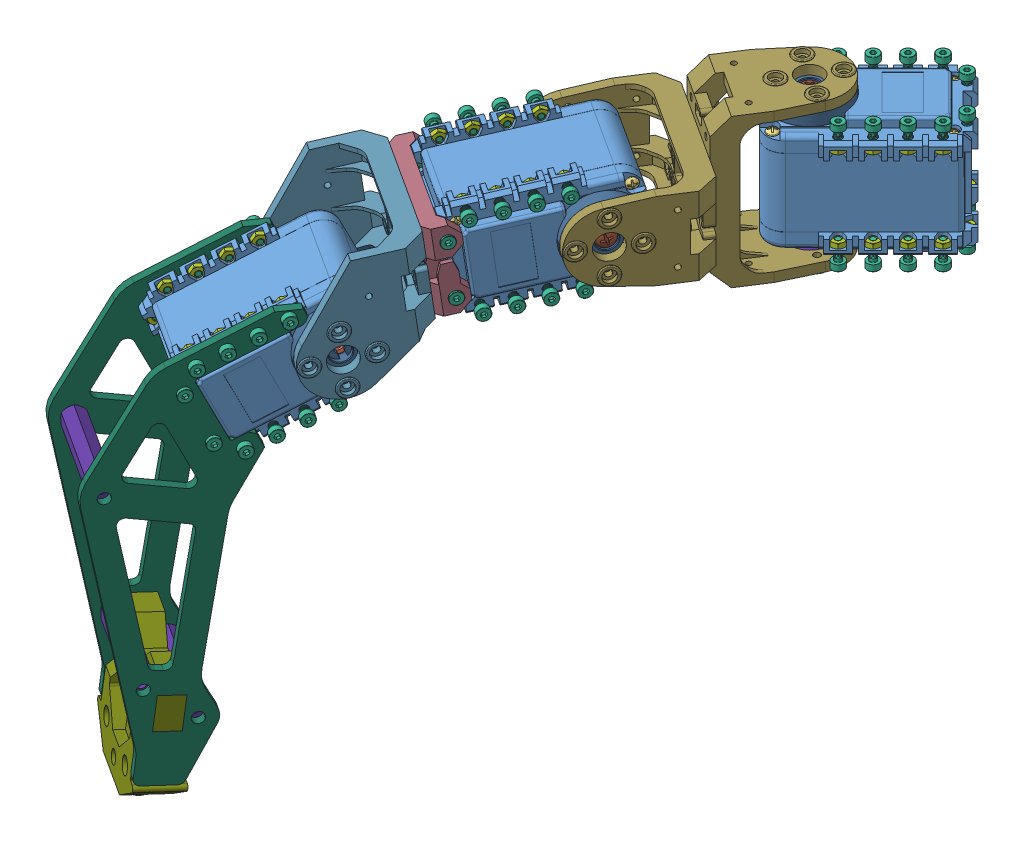
SolidWorks assembly Assambly Pedro Leg, configuration Predeterminado. Lengths in mm.
Overall size (165.19 178.65 220.71).
174 component instances, 18 part files, 61 mates.
Components (placement in the parent):
- AX-18F-1: AX-18F [Défaut] at (-83.9806 17.0398 384.115) x (-0.707107 0 -0.707107) z (0 1 0) size (32 50.04 41)
  - ASSY_DUMMY___-1: ASSY_DUMMY___ [Défaut] at origin size (32 50.04 38.37)
  - ASSY_GEAR-WHEEL___DUMMY-1: ASSY_GEAR-WHEEL___DUMMY [Défaut] at (0 0 -2) x (-1 0 0) z (0 0 1) size (6.5 6.5 5.51)
  - DX124_SCREW-COVER___-1: DX124_SCREW-COVER___ [Défaut] at (9.5 8.5 14.5) x (-1 0 0) z (0 1 0) size (3.5 30.7 3.5)
  - DX124_SCREW-COVER___-2: DX124_SCREW-COVER___ [Défaut] at (-9.5 8.5 14.5) x (-1 0 0) z (0 1 0) size (3.5 30.7 3.5)
  - DX124_SCREW-COVER___-3: DX124_SCREW-COVER___ [Défaut] at (10.5 -33 14.5) x (-1 0 0) z (0 1 0) size (3.5 30.7 3.5)
  - DX124_SCREW-COVER___-4: DX124_SCREW-COVER___ [Défaut] at (-10.5 -33 14.5) x (-1 0 0) z (0 1 0) size (3.5 30.7 3.5)
  - 099990987____-1: 099990987____ [Défaut] at (5.05 -15.19 -9.75) x (1 0 0) z (0 1 0) size (9.9 9.43 4.9)
  - 099990987____-2: 099990987____ [Défaut] at (-4.95 -15.19 -9.75) x (1 0 0) z (0 1 0) size (9.9 9.43 4.9)
  - DC04_B01_INSERT_M3-1: DC04_B01_INSERT_M3 [Défaut] at (0 0 -18.4) x (-1 0 0) z (0 1 0) size (4.98 7 4.98)
  - socket head cap screw_iso-1: socket head cap screw_iso [ISO 4762 M2 x 6 --- 6S] at (-13.5 -6.5 20.5) x (0 0 -1) z (1 0 0) size (8 3.8 3.8)
  - hex nut style 1 gradeab_iso-1: hex nut style 1 gradeab_iso [Hexagon Nut ISO - 4032 - M2 - D - S] at (-13.5 -6.5 14) x (0 1 0) z (0 0 1) size (4 4.62 1.6)
  - hex nut style 1 gradeab_iso-2: hex nut style 1 gradeab_iso [Hexagon Nut ISO - 4032 - M2 - D - S] at (-13.5 -14.5 14) x (0 1 0) z (0 0 1) size (4 4.62 1.6)
  - hex nut style 1 gradeab_iso-3: hex nut style 1 gradeab_iso [Hexagon Nut ISO - 4032 - M2 - D - S] at (-13.5 -22.5 14) x (0 1 0) z (0 0 1) size (4 4.62 1.6)
  - socket head cap screw_iso-2: socket head cap screw_iso [ISO 4762 M2 x 6 --- 6S] at (-13.5 -14.5 20.5) x (0 0 -1) z (1 0 0) size (8 3.8 3.8)
  - socket head cap screw_iso-3: socket head cap screw_iso [ISO 4762 M2 x 6 --- 6S] at (-13.5 -22.5 20.5) x (0 0 -1) z (1 0 0) size (8 3.8 3.8)
  - socket head cap screw_iso-4: socket head cap screw_iso [ISO 4762 M2 x 6 --- 6S] at (-13.5 -30.5 20.5) x (0 0 -1) z (1 0 0) size (8 3.8 3.8)
  - hex nut style 1 gradeab_iso-4: hex nut style 1 gradeab_iso [Hexagon Nut ISO - 4032 - M2 - D - S] at (-13.5 -30.5 14) x (0 1 0) z (0 0 1) size (4 4.62 1.6)
  - hex nut style 1 gradeab_iso-5: hex nut style 1 gradeab_iso [Hexagon Nut ISO - 4032 - M2 - D - S] at (13.5 -6.5 12.4001) x (0 1 0) z (0 0 -1) size (4 4.62 1.6)
  - socket head cap screw_iso-5: socket head cap screw_iso [ISO 4762 M2 x 6 --- 6S] at (13.5 -6.5 20.5) x (0 0 -1) z (1 0 0) size (8 3.8 3.8)
  - hex nut style 1 gradeab_iso-6: hex nut style 1 gradeab_iso [Hexagon Nut ISO - 4032 - M2 - D - S] at (13.5 -14.5 12.4001) x (0 1 0) z (0 0 -1) size (4 4.62 1.6)
  - hex nut style 1 gradeab_iso-7: hex nut style 1 gradeab_iso [Hexagon Nut ISO - 4032 - M2 - D - S] at (13.5 -22.5 12.4001) x (0 1 0) z (0 0 -1) size (4 4.62 1.6)
  - socket head cap screw_iso-6: socket head cap screw_iso [ISO 4762 M2 x 6 --- 6S] at (13.5 -14.5 20.5) x (0 0 -1) z (1 0 0) size (8 3.8 3.8)
  - socket head cap screw_iso-7: socket head cap screw_iso [ISO 4762 M2 x 6 --- 6S] at (13.5 -22.5 20.5) x (0 0 -1) z (1 0 0) size (8 3.8 3.8)
  - socket head cap screw_iso-8: socket head cap screw_iso [ISO 4762 M2 x 6 --- 6S] at (13.5 -30.5 20.5) x (0 0 -1) z (1 0 0) size (8 3.8 3.8)
  - hex nut style 1 gradeab_iso-8: hex nut style 1 gradeab_iso [Hexagon Nut ISO - 4032 - M2 - D - S] at (13.5 -30.5 12.4001) x (0 1 0) z (0 0 -1) size (4 4.62 1.6)
  - socket head cap screw_iso-9: socket head cap screw_iso [ISO 4762 M2 x 6 --- 6S] at (-13.5 -6.5 -20.5) x (0 0 1) z (-1 0 0) size (8 3.8 3.8)
  - hex nut style 1 gradeab_iso-9: hex nut style 1 gradeab_iso [Hexagon Nut ISO - 4032 - M2 - D - S] at (-13.5 -6.5 -12.4001) x (0 1 0) z (0 0 1) size (4 4.62 1.6)
  - hex nut style 1 gradeab_iso-10: hex nut style 1 gradeab_iso [Hexagon Nut ISO - 4032 - M2 - D - S] at (-13.5 -14.5 -12.4001) x (0 1 0) z (0 0 1) size (4 4.62 1.6)
  - hex nut style 1 gradeab_iso-11: hex nut style 1 gradeab_iso [Hexagon Nut ISO - 4032 - M2 - D - S] at (-13.5 -22.5 -12.4001) x (0 1 0) z (0 0 1) size (4 4.62 1.6)
  - socket head cap screw_iso-10: socket head cap screw_iso [ISO 4762 M2 x 6 --- 6S] at (-13.5 -14.5 -20.5) x (0 0 1) z (-1 0 0) size (8 3.8 3.8)
  - socket head cap screw_iso-11: socket head cap screw_iso [ISO 4762 M2 x 6 --- 6S] at (-13.5 -22.5 -20.5) x (0 0 1) z (-1 0 0) size (8 3.8 3.8)
  - socket head cap screw_iso-12: socket head cap screw_iso [ISO 4762 M2 x 6 --- 6S] at (-13.5 -30.5 -20.5) x (0 0 1) z (-1 0 0) size (8 3.8 3.8)
  - hex nut style 1 gradeab_iso-12: hex nut style 1 gradeab_iso [Hexagon Nut ISO - 4032 - M2 - D - S] at (-13.5 -30.5 -12.4001) x (0 1 0) z (0 0 1) size (4 4.62 1.6)
  - hex nut style 1 gradeab_iso-13: hex nut style 1 gradeab_iso [Hexagon Nut ISO - 4032 - M2 - D - S] at (13.5 -6.5 -14) x (0 1 0) z (0 0 -1) size (4 4.62 1.6)
  - socket head cap screw_iso-13: socket head cap screw_iso [ISO 4762 M2 x 6 --- 6S] at (13.5 -6.5 -20.5) x (0 0 1) z (-1 0 0) size (8 3.8 3.8)
  - hex nut style 1 gradeab_iso-14: hex nut style 1 gradeab_iso [Hexagon Nut ISO - 4032 - M2 - D - S] at (13.5 -14.5 -14) x (0 1 0) z (0 0 -1) size (4 4.62 1.6)
  - hex nut style 1 gradeab_iso-15: hex nut style 1 gradeab_iso [Hexagon Nut ISO - 4032 - M2 - D - S] at (13.5 -22.5 -14) x (0 1 0) z (0 0 -1) size (4 4.62 1.6)
  - socket head cap screw_iso-14: socket head cap screw_iso [ISO 4762 M2 x 6 --- 6S] at (13.5 -14.5 -20.5) x (0 0 1) z (-1 0 0) size (8 3.8 3.8)
  - socket head cap screw_iso-15: socket head cap screw_iso [ISO 4762 M2 x 6 --- 6S] at (13.5 -22.5 -20.5) x (0 0 1) z (-1 0 0) size (8 3.8 3.8)
  - socket head cap screw_iso-16: socket head cap screw_iso [ISO 4762 M2 x 6 --- 6S] at (13.5 -30.5 -20.5) x (0 0 1) z (-1 0 0) size (8 3.8 3.8)
  - hex nut style 1 gradeab_iso-16: hex nut style 1 gradeab_iso [Hexagon Nut ISO - 4032 - M2 - D - S] at (13.5 -30.5 -14) x (0 1 0) z (0 0 -1) size (4 4.62 1.6)
  - socket head cap screw_iso-17: socket head cap screw_iso [ISO 4762 M2 x 5 --- 5S] at (-8 -36 19.6) x (0 0 -1) z (1 0 0) size (7 3.8 3.8)
  - hex nut style 1 gradeab_iso-17: hex nut style 1 gradeab_iso [Hexagon Nut ISO - 4032 - M2 - D - S] at (-8 -36 14) x (-1 0 0) z (0 0 1) size (4 4.62 1.6)
  - hex nut style 1 gradeab_iso-18: hex nut style 1 gradeab_iso [Hexagon Nut ISO - 4032 - M2 - D - S] at (8 -36 14) x (-1 0 0) z (0 0 1) size (4 4.62 1.6)
  - socket head cap screw_iso-18: socket head cap screw_iso [ISO 4762 M2 x 5 --- 5S] at (8 -36 19.6) x (0 0 -1) z (1 0 0) size (7 3.8 3.8)
  - socket head cap screw_iso-19: socket head cap screw_iso [ISO 4762 M2 x 5 --- 5S] at (-8 -36 -19.6) x (0 0 1) z (-1 0 0) size (7 3.8 3.8)
  - hex nut style 1 gradeab_iso-19: hex nut style 1 gradeab_iso [Hexagon Nut ISO - 4032 - M2 - D - S] at (-8 -36 -12.4001) x (-1 0 0) z (0 0 1) size (4 4.62 1.6)
  - hex nut style 1 gradeab_iso-20: hex nut style 1 gradeab_iso [Hexagon Nut ISO - 4032 - M2 - D - S] at (8 -36 -12.4001) x (-1 0 0) z (0 0 1) size (4 4.62 1.6)
  - socket head cap screw_iso-20: socket head cap screw_iso [ISO 4762 M2 x 5 --- 5S] at (8 -36 -19.6) x (0 0 1) z (-1 0 0) size (7 3.8 3.8)
- PBPF-WA-1: PBPF-WA [Predeterminado] at (-83.9806 -3.0702 384.115) x (0.035761 0 0.99936) z (-0.99936 0 0.035761) size (12 1.9 12)
- PBPF-BU-1: PBPF-BU [Predeterminado] at (-83.9806 -1.4202 384.115) x (0.260833 0 0.965384) z (0.965384 0 -0.260833) size (10 7.1 10)
- DC04_B01_HORN2_DUMMY-1: DC04_B01_HORN2_DUMMY [Défaut] at (-83.9806 36.1398 384.115) x (-0.707107 0 0.707107) z (0 1 0) size (22 22 6.7)
- BHS_M2_6X8-1: BHS_M2_6X8 [Défaut] at (-83.9806 36.5898 384.115) size (5.5 9.6 5.5)
- PFP04-F2-2: PFP04-F2 [Défaut] at (-83.9806 16.9798 384.115) x (0 1 0) z (-0.542867 0 0.839819) size (48.81 25 37)
- BHS_M2_6X8-2: BHS_M2_6X8 [Défaut] at (-83.9806 -6.5202 384.115) x (-0.76654 0 0.642197) z (0.642197 0 0.76654) size (5.5 9.6 5.5)
- PFP04-F2-3: PFP04-F2 [Défaut] at (-112.2097 16.9798 427.7856) x (-0.839819 0 -0.542867) z (0.542867 0 -0.839819) size (48.81 25 37)
- AX-18F-14: AX-18F [Défaut] at (-112.1593 16.9798 427.8182) x (0.066454 -0.992479 -0.102804) z (0.839819 0 0.542867) size (32 50.04 41)
  - ASSY_DUMMY___-1: ASSY_DUMMY___ [Défaut] at origin size (32 50.04 38.37)
  - ASSY_GEAR-WHEEL___DUMMY-1: ASSY_GEAR-WHEEL___DUMMY [Défaut] at (0 0 -2) x (-1 0 0) z (0 0 1) size (6.5 6.5 5.51)
  - DX124_SCREW-COVER___-1: DX124_SCREW-COVER___ [Défaut] at (9.5 8.5 14.5) x (-1 0 0) z (0 1 0) size (3.5 30.7 3.5)
  - DX124_SCREW-COVER___-2: DX124_SCREW-COVER___ [Défaut] at (-9.5 8.5 14.5) x (-1 0 0) z (0 1 0) size (3.5 30.7 3.5)
  - DX124_SCREW-COVER___-3: DX124_SCREW-COVER___ [Défaut] at (10.5 -33 14.5) x (-1 0 0) z (0 1 0) size (3.5 30.7 3.5)
  - DX124_SCREW-COVER___-4: DX124_SCREW-COVER___ [Défaut] at (-10.5 -33 14.5) x (-1 0 0) z (0 1 0) size (3.5 30.7 3.5)
  - 099990987____-1: 099990987____ [Défaut] at (5.05 -15.19 -9.75) x (1 0 0) z (0 1 0) size (9.9 9.43 4.9)
  - 099990987____-2: 099990987____ [Défaut] at (-4.95 -15.19 -9.75) x (1 0 0) z (0 1 0) size (9.9 9.43 4.9)
  - DC04_B01_INSERT_M3-1: DC04_B01_INSERT_M3 [Défaut] at (0 0 -18.4) x (-1 0 0) z (0 1 0) size (4.98 7 4.98)
  - socket head cap screw_iso-1: socket head cap screw_iso [ISO 4762 M2 x 6 --- 6S] at (-13.5 -6.5 20.5) x (0 0 -1) z (1 0 0) size (8 3.8 3.8)
  - hex nut style 1 gradeab_iso-1: hex nut style 1 gradeab_iso [Hexagon Nut ISO - 4032 - M2 - D - S] at (-13.5 -6.5 14) x (0 1 0) z (0 0 1) size (4 4.62 1.6)
  - hex nut style 1 gradeab_iso-2: hex nut style 1 gradeab_iso [Hexagon Nut ISO - 4032 - M2 - D - S] at (-13.5 -14.5 14) x (0 1 0) z (0 0 1) size (4 4.62 1.6)
  - hex nut style 1 gradeab_iso-3: hex nut style 1 gradeab_iso [Hexagon Nut ISO - 4032 - M2 - D - S] at (-13.5 -22.5 14) x (0 1 0) z (0 0 1) size (4 4.62 1.6)
  - socket head cap screw_iso-2: socket head cap screw_iso [ISO 4762 M2 x 6 --- 6S] at (-13.5 -14.5 20.5) x (0 0 -1) z (1 0 0) size (8 3.8 3.8)
  - socket head cap screw_iso-3: socket head cap screw_iso [ISO 4762 M2 x 6 --- 6S] at (-13.5 -22.5 20.5) x (0 0 -1) z (1 0 0) size (8 3.8 3.8)
  - socket head cap screw_iso-4: socket head cap screw_iso [ISO 4762 M2 x 6 --- 6S] at (-13.5 -30.5 20.5) x (0 0 -1) z (1 0 0) size (8 3.8 3.8)
  - hex nut style 1 gradeab_iso-4: hex nut style 1 gradeab_iso [Hexagon Nut ISO - 4032 - M2 - D - S] at (-13.5 -30.5 14) x (0 1 0) z (0 0 1) size (4 4.62 1.6)
  - hex nut style 1 gradeab_iso-5: hex nut style 1 gradeab_iso [Hexagon Nut ISO - 4032 - M2 - D - S] at (13.5 -6.5 12.4001) x (0 1 0) z (0 0 -1) size (4 4.62 1.6)
  - socket head cap screw_iso-5: socket head cap screw_iso [ISO 4762 M2 x 6 --- 6S] at (13.5 -6.5 20.5) x (0 0 -1) z (1 0 0) size (8 3.8 3.8)
  - hex nut style 1 gradeab_iso-6: hex nut style 1 gradeab_iso [Hexagon Nut ISO - 4032 - M2 - D - S] at (13.5 -14.5 12.4001) x (0 1 0) z (0 0 -1) size (4 4.62 1.6)
  - hex nut style 1 gradeab_iso-7: hex nut style 1 gradeab_iso [Hexagon Nut ISO - 4032 - M2 - D - S] at (13.5 -22.5 12.4001) x (0 1 0) z (0 0 -1) size (4 4.62 1.6)
  - socket head cap screw_iso-6: socket head cap screw_iso [ISO 4762 M2 x 6 --- 6S] at (13.5 -14.5 20.5) x (0 0 -1) z (1 0 0) size (8 3.8 3.8)
  - socket head cap screw_iso-7: socket head cap screw_iso [ISO 4762 M2 x 6 --- 6S] at (13.5 -22.5 20.5) x (0 0 -1) z (1 0 0) size (8 3.8 3.8)
  - socket head cap screw_iso-8: socket head cap screw_iso [ISO 4762 M2 x 6 --- 6S] at (13.5 -30.5 20.5) x (0 0 -1) z (1 0 0) size (8 3.8 3.8)
  - hex nut style 1 gradeab_iso-8: hex nut style 1 gradeab_iso [Hexagon Nut ISO - 4032 - M2 - D - S] at (13.5 -30.5 12.4001) x (0 1 0) z (0 0 -1) size (4 4.62 1.6)
  - socket head cap screw_iso-9: socket head cap screw_iso [ISO 4762 M2 x 6 --- 6S] at (-13.5 -6.5 -20.5) x (0 0 1) z (-1 0 0) size (8 3.8 3.8)
  - hex nut style 1 gradeab_iso-9: hex nut style 1 gradeab_iso [Hexagon Nut ISO - 4032 - M2 - D - S] at (-13.5 -6.5 -12.4001) x (0 1 0) z (0 0 1) size (4 4.62 1.6)
  - hex nut style 1 gradeab_iso-10: hex nut style 1 gradeab_iso [Hexagon Nut ISO - 4032 - M2 - D - S] at (-13.5 -14.5 -12.4001) x (0 1 0) z (0 0 1) size (4 4.62 1.6)
  - hex nut style 1 gradeab_iso-11: hex nut style 1 gradeab_iso [Hexagon Nut ISO - 4032 - M2 - D - S] at (-13.5 -22.5 -12.4001) x (0 1 0) z (0 0 1) size (4 4.62 1.6)
  - socket head cap screw_iso-10: socket head cap screw_iso [ISO 4762 M2 x 6 --- 6S] at (-13.5 -14.5 -20.5) x (0 0 1) z (-1 0 0) size (8 3.8 3.8)
  - socket head cap screw_iso-11: socket head cap screw_iso [ISO 4762 M2 x 6 --- 6S] at (-13.5 -22.5 -20.5) x (0 0 1) z (-1 0 0) size (8 3.8 3.8)
  - socket head cap screw_iso-12: socket head cap screw_iso [ISO 4762 M2 x 6 --- 6S] at (-13.5 -30.5 -20.5) x (0 0 1) z (-1 0 0) size (8 3.8 3.8)
  - hex nut style 1 gradeab_iso-12: hex nut style 1 gradeab_iso [Hexagon Nut ISO - 4032 - M2 - D - S] at (-13.5 -30.5 -12.4001) x (0 1 0) z (0 0 1) size (4 4.62 1.6)
  - hex nut style 1 gradeab_iso-13: hex nut style 1 gradeab_iso [Hexagon Nut ISO - 4032 - M2 - D - S] at (13.5 -6.5 -14) x (0 1 0) z (0 0 -1) size (4 4.62 1.6)
  - socket head cap screw_iso-13: socket head cap screw_iso [ISO 4762 M2 x 6 --- 6S] at (13.5 -6.5 -20.5) x (0 0 1) z (-1 0 0) size (8 3.8 3.8)
  - hex nut style 1 gradeab_iso-14: hex nut style 1 gradeab_iso [Hexagon Nut ISO - 4032 - M2 - D - S] at (13.5 -14.5 -14) x (0 1 0) z (0 0 -1) size (4 4.62 1.6)
  - hex nut style 1 gradeab_iso-15: hex nut style 1 gradeab_iso [Hexagon Nut ISO - 4032 - M2 - D - S] at (13.5 -22.5 -14) x (0 1 0) z (0 0 -1) size (4 4.62 1.6)
  - socket head cap screw_iso-14: socket head cap screw_iso [ISO 4762 M2 x 6 --- 6S] at (13.5 -14.5 -20.5) x (0 0 1) z (-1 0 0) size (8 3.8 3.8)
  - socket head cap screw_iso-15: socket head cap screw_iso [ISO 4762 M2 x 6 --- 6S] at (13.5 -22.5 -20.5) x (0 0 1) z (-1 0 0) size (8 3.8 3.8)
  - socket head cap screw_iso-16: socket head cap screw_iso [ISO 4762 M2 x 6 --- 6S] at (13.5 -30.5 -20.5) x (0 0 1) z (-1 0 0) size (8 3.8 3.8)
  - hex nut style 1 gradeab_iso-16: hex nut style 1 gradeab_iso [Hexagon Nut ISO - 4032 - M2 - D - S] at (13.5 -30.5 -14) x (0 1 0) z (0 0 -1) size (4 4.62 1.6)
  - socket head cap screw_iso-17: socket head cap screw_iso [ISO 4762 M2 x 5 --- 5S] at (-8 -36 19.6) x (0 0 -1) z (1 0 0) size (7 3.8 3.8)
  - hex nut style 1 gradeab_iso-17: hex nut style 1 gradeab_iso [Hexagon Nut ISO - 4032 - M2 - D - S] at (-8 -36 14) x (-1 0 0) z (0 0 1) size (4 4.62 1.6)
  - hex nut style 1 gradeab_iso-18: hex nut style 1 gradeab_iso [Hexagon Nut ISO - 4032 - M2 - D - S] at (8 -36 14) x (-1 0 0) z (0 0 1) size (4 4.62 1.6)
  - socket head cap screw_iso-18: socket head cap screw_iso [ISO 4762 M2 x 5 --- 5S] at (8 -36 19.6) x (0 0 -1) z (1 0 0) size (7 3.8 3.8)
  - socket head cap screw_iso-19: socket head cap screw_iso [ISO 4762 M2 x 5 --- 5S] at (-8 -36 -19.6) x (0 0 1) z (-1 0 0) size (7 3.8 3.8)
  - hex nut style 1 gradeab_iso-19: hex nut style 1 gradeab_iso [Hexagon Nut ISO - 4032 - M2 - D - S] at (-8 -36 -12.4001) x (-1 0 0) z (0 0 1) size (4 4.62 1.6)
  - hex nut style 1 gradeab_iso-20: hex nut style 1 gradeab_iso [Hexagon Nut ISO - 4032 - M2 - D - S] at (8 -36 -12.4001) x (-1 0 0) z (0 0 1) size (4 4.62 1.6)
  - socket head cap screw_iso-20: socket head cap screw_iso [ISO 4762 M2 x 5 --- 5S] at (8 -36 -19.6) x (0 0 1) z (-1 0 0) size (7 3.8 3.8)
- DC04_B01_HORN2_DUMMY-2: DC04_B01_HORN2_DUMMY [Défaut] at (-96.1188 16.9798 438.1869) x (0.538784 0.122412 -0.833503) z (0.839819 0 0.542867) size (22 22 6.7)
- PBPF-BU-2: PBPF-BU [Predeterminado] at (-127.6624 16.9798 417.7968) x (-0.044176 0.996684 0.06834) z (-0.541067 -0.081375 0.837034) size (10 7.1 10)
- PBPF-WA-3: PBPF-WA [Predeterminado] at (-129.0481 16.9798 416.9011) x (-0.044176 -0.996684 0.06834) z (-0.541067 0.081375 0.837034) size (12 1.9 12)
- BHS_M2_6X8-3: BHS_M2_6X8 [Défaut] at (-95.7409 16.9798 438.4312) x (-0.514229 -0.320506 0.795515) z (-0.173992 0.947246 0.269167) size (5.5 9.6 5.5)
- BHS_M2_6X8-4: BHS_M2_6X8 [Défaut] at (-131.9455 16.9798 415.0282) x (-0.427933 0.615311 0.662016) z (-0.334032 -0.788284 0.51675) size (5.5 9.6 5.5)
- PFP04-F3-1: PFP04-F3 [Défaut] at (-134.5189 11.8997 462.4085) x (-0.066454 0.992479 0.102804) z (-0.839819 0 -0.542867) size (25 9 38)
- PFP04-F1-1: PFP04-F1 [Défaut] at (-145.9473 -5.3067 480.0884) x (-0.839819 0 -0.542867) z (0.538784 0.122412 -0.833503) size (48.81 38 34)
- PBPF-BU-3: PBPF-BU [Predeterminado] at (-161.4 -5.3067 470.0997) x (-0.258394 0.879456 0.399737) z (-0.477428 -0.47598 0.738584) size (10 7.1 10)
- PBPF-WA-4: PBPF-WA [Predeterminado] at (-162.7857 -5.3067 469.2039) x (-0.040206 -0.997254 0.062198) z (-0.541376 0.074062 0.837512) size (12 1.9 12)
- DC04_B01_HORN2_DUMMY-3: DC04_B01_HORN2_DUMMY [Défaut] at (-129.8564 -5.3067 490.4898) x (0.206992 -0.924454 -0.320218) z (0.839819 0 0.542867) size (22 22 6.7)
- AX-18F-15: AX-18F [Défaut] at (-145.8969 -5.3067 480.121) x (0.229741 -0.906036 -0.355412) z (0.839819 0 0.542867) size (32 50.04 41)
  - ASSY_DUMMY___-1: ASSY_DUMMY___ [Défaut] at origin size (32 50.04 38.37)
  - ASSY_GEAR-WHEEL___DUMMY-1: ASSY_GEAR-WHEEL___DUMMY [Défaut] at (0 0 -2) x (-1 0 0) z (0 0 1) size (6.5 6.5 5.51)
  - DX124_SCREW-COVER___-1: DX124_SCREW-COVER___ [Défaut] at (9.5 8.5 14.5) x (-1 0 0) z (0 1 0) size (3.5 30.7 3.5)
  - DX124_SCREW-COVER___-2: DX124_SCREW-COVER___ [Défaut] at (-9.5 8.5 14.5) x (-1 0 0) z (0 1 0) size (3.5 30.7 3.5)
  - DX124_SCREW-COVER___-3: DX124_SCREW-COVER___ [Défaut] at (10.5 -33 14.5) x (-1 0 0) z (0 1 0) size (3.5 30.7 3.5)
  - DX124_SCREW-COVER___-4: DX124_SCREW-COVER___ [Défaut] at (-10.5 -33 14.5) x (-1 0 0) z (0 1 0) size (3.5 30.7 3.5)
  - 099990987____-1: 099990987____ [Défaut] at (5.05 -15.19 -9.75) x (1 0 0) z (0 1 0) size (9.9 9.43 4.9)
  - 099990987____-2: 099990987____ [Défaut] at (-4.95 -15.19 -9.75) x (1 0 0) z (0 1 0) size (9.9 9.43 4.9)
  - DC04_B01_INSERT_M3-1: DC04_B01_INSERT_M3 [Défaut] at (0 0 -18.4) x (-1 0 0) z (0 1 0) size (4.98 7 4.98)
  - socket head cap screw_iso-1: socket head cap screw_iso [ISO 4762 M2 x 6 --- 6S] at (-13.5 -6.5 20.5) x (0 0 -1) z (1 0 0) size (8 3.8 3.8)
  - hex nut style 1 gradeab_iso-1: hex nut style 1 gradeab_iso [Hexagon Nut ISO - 4032 - M2 - D - S] at (-13.5 -6.5 14) x (0 1 0) z (0 0 1) size (4 4.62 1.6)
  - hex nut style 1 gradeab_iso-2: hex nut style 1 gradeab_iso [Hexagon Nut ISO - 4032 - M2 - D - S] at (-13.5 -14.5 14) x (0 1 0) z (0 0 1) size (4 4.62 1.6)
  - hex nut style 1 gradeab_iso-3: hex nut style 1 gradeab_iso [Hexagon Nut ISO - 4032 - M2 - D - S] at (-13.5 -22.5 14) x (0 1 0) z (0 0 1) size (4 4.62 1.6)
  - socket head cap screw_iso-2: socket head cap screw_iso [ISO 4762 M2 x 6 --- 6S] at (-13.5 -14.5 20.5) x (0 0 -1) z (1 0 0) size (8 3.8 3.8)
  - socket head cap screw_iso-3: socket head cap screw_iso [ISO 4762 M2 x 6 --- 6S] at (-13.5 -22.5 20.5) x (0 0 -1) z (1 0 0) size (8 3.8 3.8)
  - socket head cap screw_iso-4: socket head cap screw_iso [ISO 4762 M2 x 6 --- 6S] at (-13.5 -30.5 20.5) x (0 0 -1) z (1 0 0) size (8 3.8 3.8)
  - hex nut style 1 gradeab_iso-4: hex nut style 1 gradeab_iso [Hexagon Nut ISO - 4032 - M2 - D - S] at (-13.5 -30.5 14) x (0 1 0) z (0 0 1) size (4 4.62 1.6)
  - hex nut style 1 gradeab_iso-5: hex nut style 1 gradeab_iso [Hexagon Nut ISO - 4032 - M2 - D - S] at (13.5 -6.5 12.4001) x (0 1 0) z (0 0 -1) size (4 4.62 1.6)
  - socket head cap screw_iso-5: socket head cap screw_iso [ISO 4762 M2 x 6 --- 6S] at (13.5 -6.5 20.5) x (0 0 -1) z (1 0 0) size (8 3.8 3.8)
  - hex nut style 1 gradeab_iso-6: hex nut style 1 gradeab_iso [Hexagon Nut ISO - 4032 - M2 - D - S] at (13.5 -14.5 12.4001) x (0 1 0) z (0 0 -1) size (4 4.62 1.6)
  - hex nut style 1 gradeab_iso-7: hex nut style 1 gradeab_iso [Hexagon Nut ISO - 4032 - M2 - D - S] at (13.5 -22.5 12.4001) x (0 1 0) z (0 0 -1) size (4 4.62 1.6)
  - socket head cap screw_iso-6: socket head cap screw_iso [ISO 4762 M2 x 6 --- 6S] at (13.5 -14.5 20.5) x (0 0 -1) z (1 0 0) size (8 3.8 3.8)
  - socket head cap screw_iso-7: socket head cap screw_iso [ISO 4762 M2 x 6 --- 6S] at (13.5 -22.5 20.5) x (0 0 -1) z (1 0 0) size (8 3.8 3.8)
  - socket head cap screw_iso-8: socket head cap screw_iso [ISO 4762 M2 x 6 --- 6S] at (13.5 -30.5 20.5) x (0 0 -1) z (1 0 0) size (8 3.8 3.8)
  - hex nut style 1 gradeab_iso-8: hex nut style 1 gradeab_iso [Hexagon Nut ISO - 4032 - M2 - D - S] at (13.5 -30.5 12.4001) x (0 1 0) z (0 0 -1) size (4 4.62 1.6)
  - socket head cap screw_iso-9: socket head cap screw_iso [ISO 4762 M2 x 6 --- 6S] at (-13.5 -6.5 -20.5) x (0 0 1) z (-1 0 0) size (8 3.8 3.8)
  - hex nut style 1 gradeab_iso-9: hex nut style 1 gradeab_iso [Hexagon Nut ISO - 4032 - M2 - D - S] at (-13.5 -6.5 -12.4001) x (0 1 0) z (0 0 1) size (4 4.62 1.6)
  - hex nut style 1 gradeab_iso-10: hex nut style 1 gradeab_iso [Hexagon Nut ISO - 4032 - M2 - D - S] at (-13.5 -14.5 -12.4001) x (0 1 0) z (0 0 1) size (4 4.62 1.6)
  - hex nut style 1 gradeab_iso-11: hex nut style 1 gradeab_iso [Hexagon Nut ISO - 4032 - M2 - D - S] at (-13.5 -22.5 -12.4001) x (0 1 0) z (0 0 1) size (4 4.62 1.6)
  - socket head cap screw_iso-10: socket head cap screw_iso [ISO 4762 M2 x 6 --- 6S] at (-13.5 -14.5 -20.5) x (0 0 1) z (-1 0 0) size (8 3.8 3.8)
  - socket head cap screw_iso-11: socket head cap screw_iso [ISO 4762 M2 x 6 --- 6S] at (-13.5 -22.5 -20.5) x (0 0 1) z (-1 0 0) size (8 3.8 3.8)
  - socket head cap screw_iso-12: socket head cap screw_iso [ISO 4762 M2 x 6 --- 6S] at (-13.5 -30.5 -20.5) x (0 0 1) z (-1 0 0) size (8 3.8 3.8)
  - hex nut style 1 gradeab_iso-12: hex nut style 1 gradeab_iso [Hexagon Nut ISO - 4032 - M2 - D - S] at (-13.5 -30.5 -12.4001) x (0 1 0) z (0 0 1) size (4 4.62 1.6)
  - hex nut style 1 gradeab_iso-13: hex nut style 1 gradeab_iso [Hexagon Nut ISO - 4032 - M2 - D - S] at (13.5 -6.5 -14) x (0 1 0) z (0 0 -1) size (4 4.62 1.6)
  - socket head cap screw_iso-13: socket head cap screw_iso [ISO 4762 M2 x 6 --- 6S] at (13.5 -6.5 -20.5) x (0 0 1) z (-1 0 0) size (8 3.8 3.8)
  - hex nut style 1 gradeab_iso-14: hex nut style 1 gradeab_iso [Hexagon Nut ISO - 4032 - M2 - D - S] at (13.5 -14.5 -14) x (0 1 0) z (0 0 -1) size (4 4.62 1.6)
  - hex nut style 1 gradeab_iso-15: hex nut style 1 gradeab_iso [Hexagon Nut ISO - 4032 - M2 - D - S] at (13.5 -22.5 -14) x (0 1 0) z (0 0 -1) size (4 4.62 1.6)
  - socket head cap screw_iso-14: socket head cap screw_iso [ISO 4762 M2 x 6 --- 6S] at (13.5 -14.5 -20.5) x (0 0 1) z (-1 0 0) size (8 3.8 3.8)
  - socket head cap screw_iso-15: socket head cap screw_iso [ISO 4762 M2 x 6 --- 6S] at (13.5 -22.5 -20.5) x (0 0 1) z (-1 0 0) size (8 3.8 3.8)
  - socket head cap screw_iso-16: socket head cap screw_iso [ISO 4762 M2 x 6 --- 6S] at (13.5 -30.5 -20.5) x (0 0 1) z (-1 0 0) size (8 3.8 3.8)
  - hex nut style 1 gradeab_iso-16: hex nut style 1 gradeab_iso [Hexagon Nut ISO - 4032 - M2 - D - S] at (13.5 -30.5 -14) x (0 1 0) z (0 0 -1) size (4 4.62 1.6)
  - socket head cap screw_iso-17: socket head cap screw_iso [ISO 4762 M2 x 5 --- 5S] at (-8 -36 19.6) x (0 0 -1) z (1 0 0) size (7 3.8 3.8)
  - hex nut style 1 gradeab_iso-17: hex nut style 1 gradeab_iso [Hexagon Nut ISO - 4032 - M2 - D - S] at (-8 -36 14) x (-1 0 0) z (0 0 1) size (4 4.62 1.6)
  - hex nut style 1 gradeab_iso-18: hex nut style 1 gradeab_iso [Hexagon Nut ISO - 4032 - M2 - D - S] at (8 -36 14) x (-1 0 0) z (0 0 1) size (4 4.62 1.6)
  - socket head cap screw_iso-18: socket head cap screw_iso [ISO 4762 M2 x 5 --- 5S] at (8 -36 19.6) x (0 0 -1) z (1 0 0) size (7 3.8 3.8)
  - socket head cap screw_iso-19: socket head cap screw_iso [ISO 4762 M2 x 5 --- 5S] at (-8 -36 -19.6) x (0 0 1) z (-1 0 0) size (7 3.8 3.8)
  - hex nut style 1 gradeab_iso-19: hex nut style 1 gradeab_iso [Hexagon Nut ISO - 4032 - M2 - D - S] at (-8 -36 -12.4001) x (-1 0 0) z (0 0 1) size (4 4.62 1.6)
  - hex nut style 1 gradeab_iso-20: hex nut style 1 gradeab_iso [Hexagon Nut ISO - 4032 - M2 - D - S] at (8 -36 -12.4001) x (-1 0 0) z (0 0 1) size (4 4.62 1.6)
  - socket head cap screw_iso-20: socket head cap screw_iso [ISO 4762 M2 x 5 --- 5S] at (8 -36 -19.6) x (0 0 1) z (-1 0 0) size (7 3.8 3.8)
- PTibiaSidePlate-1: PTibiaSidePlate [Predeterminado] at (-182.9595 -76.1207 569.2328) x (-0.491857 -0.4232 0.760906) z (-0.839819 0 -0.542867) size (89.6 107.6 2.5)
- PTibiaSidePlate-2: PTibiaSidePlate [Predeterminado] at (-211.9333 -76.1207 550.5039) x (-0.491857 -0.4232 0.760906) z (-0.839819 0 -0.542867) size (89.6 107.6 2.5)
- PFoot-1: PFoot [Défaut] at (-165.1777 -98.6842 509.9484) x (0.839819 0 0.542867) z (-0.53948 0.111537 0.834579) size (37.94 40 13)
- PStandoff-1: PStandoff [Predeterminado] at (-169.8173 -94.9232 518.968) x (0.542867 0 -0.839819) z (0.839819 0 0.542867) size (6 7.62 30)
- PStandoff-2: PStandoff [Predeterminado] at (-163.6755 -104.4419 507.6246) x (0.542867 0 -0.839819) z (0.839819 0 0.542867) size (6 7.62 30)
- PStandoff-3: PStandoff [Predeterminado] at (-175.6247 -39.8792 526.11) x (0.542867 0 -0.839819) z (0.839819 0 0.542867) size (6 7.62 30)
- PRubber Foot-1: PRubber Foot [Predeterminado] at (-169.064 -131.0879 515.9605) x (0.859115 -0.099662 -0.501984) z (-0.508187 -0.050079 -0.859789) size (9.6 5.5 9.6)
Mates (geometry in assembly coordinates):
- Concéntrica12: concentric anti-aligned: cylinder of AX-18F-1/ASSY_GEAR-WHEEL___DUMMY-1 through (-83.9806 34.9398 384.115) axis (0 1 0) radius 2.9; cylinder of DC04_B01_HORN2_DUMMY-1 through (-83.9806 31.2798 384.115) axis (0 -1 0) radius 2.95
- Paralelo1: parallel aligned: plane of AX-18F-1/ASSY_DUMMY___-1 through (-88.8243 33.4398 388.8173) normal (0.707107 0 0.707107); plane of DC04_B01_HORN2_DUMMY-1 through (-91.7195 38.1398 391.5043) normal (0.707107 0 0.707107)
- Concéntrica13: concentric anti-aligned: cylinder of AX-18F-1/ASSY_GEAR-WHEEL___DUMMY-1 through (-83.9806 14.7148 384.115) axis (0 1 0) radius 1.15; cylinder of BHS_M2_6X8-1 through (-83.9806 38.6698 384.115) axis (0 -1 0) radius 1.3
- Coincidente11: coincident anti-aligned: plane of DC04_B01_HORN2_DUMMY-1 through (-83.9806 36.5898 384.115) normal (0 1 0); plane of BHS_M2_6X8-1 through (-83.9806 36.5898 384.115) normal (0 -1 0)
- Coincidente20: coincident anti-aligned: plane of AX-18F-1/ASSY_GEAR-WHEEL___DUMMY-1 through (-83.9806 34.9398 384.115) normal (0 1 0); plane of DC04_B01_HORN2_DUMMY-1 through (-83.9806 34.9398 384.115) normal (0 -1 0)
- Concéntrica16: concentric anti-aligned: circle of DC04_B01_HORN2_DUMMY-1; cylinder of PFP04-F2-2 through (-83.9806 40.9798 384.115) axis (0 1 0) radius 4
- Coincidente21: coincident anti-aligned: plane of DC04_B01_HORN2_DUMMY-1 through (-83.9806 37.9798 384.115) normal (0 1 0); plane of PFP04-F2-2 through (-83.9806 37.9798 384.115) normal (0 -1 0)
- Concéntrica18: concentric anti-aligned: cylinder of AX-18F-1/DC04_B01_INSERT_M3-1 through (-83.9806 5.6398 384.115) axis (0 1 0) radius 1.25; cylinder of PBPF-BU-1 through (-83.9806 -1.4202 384.115) axis (0 -1 0) radius 1.6
- Coincidente24: coincident anti-aligned: plane of PBPF-BU-1 through (-83.9806 -7.0202 384.115) normal (0 1 0); plane of PFP04-F2-2 through (-83.9806 -7.0202 384.115) normal (0 -1 0)
- Concéntrica19: concentric anti-aligned: cylinder of PBPF-WA-1 through (-83.9806 -2.1202 384.115) axis (0 -1 0) radius 4.025; cylinder of PBPF-BU-1 through (-83.9806 -7.0202 384.115) axis (0 1 0) radius 4
- Coincidente25: coincident anti-aligned: plane of PBPF-WA-1 through (-83.9806 -4.0202 384.115) normal (0 -1 0); plane of PFP04-F2-2 through (-83.9806 -4.0202 384.115) normal (0 1 0)
- Concéntrica20: concentric anti-aligned: cylinder of PBPF-BU-1 through (-83.9806 -1.4202 384.115) axis (0 -1 0) radius 1.6; cylinder of BHS_M2_6X8-2 through (-83.9806 -8.6002 384.115) axis (0 1 0) radius 1.3
- Coincidente26: coincident anti-aligned: plane of PBPF-BU-1 through (-83.9806 -6.5202 384.115) normal (0 -1 0); plane of BHS_M2_6X8-2 through (-83.9806 -6.5202 384.115) normal (0 1 0)
- Concéntrica23: concentric anti-aligned: cylinder of PFP04-F2-2 through (-104.8137 24.9798 401.6074) axis (-0.542867 0 0.839819) radius 1.05; cylinder of PFP04-F2-3 through (-104.8137 24.9798 401.6074) axis (0.542867 0 -0.839819) radius 1.05
- Coincidente28: coincident anti-aligned: plane of PFP04-F2-2 through (-108.5929 -7.0202 399.1645) normal (-0.542867 0 0.839819); plane of PFP04-F2-3 through (-77.9395 29.4798 418.9791) normal (0.542867 0 -0.839819)
- Concéntrica24: concentric anti-aligned: cylinder of PFP04-F2-2 through (-91.3766 8.9798 410.2932) axis (-0.542867 0 0.839819) radius 1.05; cylinder of PFP04-F2-3 through (-91.3766 8.9798 410.2932) axis (0.542867 0 -0.839819) radius 1.05
- Concéntrica25: concentric anti-aligned: circle of PFP04-F2-3; circle of DC04_B01_HORN2_DUMMY-2
- Coincidente29: coincident anti-aligned: plane of PFP04-F2-3 through (-94.5735 16.9798 439.1858) normal (-0.839819 0 -0.542867); plane of DC04_B01_HORN2_DUMMY-2 through (-94.5735 16.9798 439.1858) normal (0.839819 0 0.542867)
- Concéntrica27: concentric anti-aligned: cylinder of AX-18F-14/ASSY_GEAR-WHEEL___DUMMY-1 through (-114.1119 16.9798 426.556) axis (0.839819 0 0.542867) radius 1.15; cylinder of DC04_B01_HORN2_DUMMY-2 through (-100.2003 16.9798 435.5486) axis (-0.839819 0 -0.542867) radius 1.3
- Coincidente36: coincident anti-aligned: plane of AX-18F-14/ASSY_GEAR-WHEEL___DUMMY-1 through (-97.1266 16.9798 437.5355) normal (0.839819 0 0.542867); plane of DC04_B01_HORN2_DUMMY-2 through (-97.1266 16.9798 437.5355) normal (-0.839819 0 -0.542867)
- Coincidente37: coincident anti-aligned: circle of AX-18F-14/ASSY_DUMMY___-1; cylinder of PBPF-BU-2 through (-132.3654 16.9798 414.7568) axis (0.839819 0 0.542867) radius 4
- Coincidente39: coincident anti-aligned: plane of PFP04-F2-3 through (-132.3654 16.9798 414.7568) normal (-0.839819 0 -0.542867); plane of PBPF-BU-2 through (-132.3654 16.9798 414.7568) normal (0.839819 0 0.542867)
- Concéntrica30: concentric anti-aligned: cylinder of PBPF-BU-2 through (-132.3654 16.9798 414.7568) axis (0.839819 0 0.542867) radius 4; cylinder of PBPF-WA-3 through (-128.2503 16.9798 417.4168) axis (-0.839819 0 -0.542867) radius 4.025
- Coincidente40: coincident anti-aligned: plane of PFP04-F2-3 through (-129.8459 16.9798 416.3854) normal (0.839819 0 0.542867); plane of PBPF-WA-3 through (-129.8459 16.9798 416.3854) normal (-0.839819 0 -0.542867)
- Concéntrica31: concentric anti-aligned: cylinder of AX-18F-14/ASSY_GEAR-WHEEL___DUMMY-1 through (-114.1119 16.9798 426.556) axis (0.839819 0 0.542867) radius 1.15; cylinder of BHS_M2_6X8-3 through (-93.994 16.9798 439.5604) axis (-0.839819 0 -0.542867) radius 1.3
- Coincidente41: coincident anti-aligned: plane of DC04_B01_HORN2_DUMMY-2 through (-95.7409 16.9798 438.4312) normal (0.839819 0 0.542867); plane of BHS_M2_6X8-3 through (-95.7409 16.9798 438.4312) normal (-0.839819 0 -0.542867)
- Concéntrica32: concentric aligned: cylinder of AX-18F-14/DC04_B01_INSERT_M3-1 through (-121.7333 16.9798 421.6295) axis (0.839819 0 0.542867) radius 1.25; cylinder of BHS_M2_6X8-4 through (-133.6923 16.9798 413.899) axis (0.839819 0 0.542867) radius 1.3
- Coincidente42: coincident anti-aligned: plane of PBPF-BU-2 through (-131.9455 16.9798 415.0282) normal (-0.839819 0 -0.542867); plane of BHS_M2_6X8-4 through (-131.9455 16.9798 415.0282) normal (0.839819 0 0.542867)
- Concéntrica33: concentric anti-aligned: cylinder of AX-18F-14/socket head cap screw_iso-17 through (-88.9625 20.5128 486.5229) axis (0.839819 0 0.542867) radius 1; cylinder of PFP04-F3-1 through (-148.0437 20.5128 448.3322) axis (-0.839819 0 -0.542867) radius 1.05
- Coincidente44: coincident anti-aligned: plane of AX-18F-14/socket head cap screw_iso-17 through (-116.2827 20.7454 466.6175) normal (-0.839819 0 -0.542867); plane of PFP04-F3-1 through (-119.7381 11.8997 471.963) normal (0.839819 0 0.542867)
- Concéntrica34: concentric aligned: cylinder of AX-18F-14/socket head cap screw_iso-20 through (-174.1486 4.6331 429.1256) axis (-0.839819 0 -0.542867) radius 1; cylinder of PFP04-F3-1 through (-146.9805 4.6331 446.6874) axis (-0.839819 0 -0.542867) radius 1.05
- Concéntrica35: concentric anti-aligned: cylinder of PFP04-F3-1 through (-141.7691 19.8395 458.888) axis (-0.538784 -0.122412 0.833503) radius 1.05; cylinder of PFP04-F1-1 through (-141.7691 19.8395 458.888) axis (0.538784 0.122412 -0.833503) radius 1.05
- Concéntrica36: concentric anti-aligned: cylinder of PFP04-F3-1 through (-128.332 19.8395 467.5739) axis (-0.538784 -0.122412 0.833503) radius 1.05; cylinder of PFP04-F1-1 through (-128.332 19.8395 467.5739) axis (0.538784 0.122412 -0.833503) radius 1.05
- Coincidente45: coincident anti-aligned: plane of PFP04-F3-1 through (-134.5189 11.8997 462.4085) normal (-0.538784 -0.122412 0.833503); plane of PFP04-F1-1 through (-115.1939 24.3057 476.7224) normal (0.538784 0.122412 -0.833503)
- Paralelo5: parallel aligned: plane of AX-18F-14/ASSY_DUMMY___-1 through (-95.0081 17.9053 430.9424) normal (0.066454 -0.992479 -0.102804); plane of DC04_B01_HORN2_DUMMY-2 through (-88.5305 18.5714 430.1318) normal (0.066454 -0.992479 -0.102804)
- Concéntrica37: concentric aligned: cylinder of PFP04-F1-1 through (-166.103 -5.3067 467.0596) axis (-0.839819 0 -0.542867) radius 4; cylinder of DC04_B01_HORN2_DUMMY-3 through (-133.9379 -5.3067 487.8514) axis (-0.839819 0 -0.542867) radius 1.3
- Coincidente47: coincident anti-aligned: plane of PFP04-F1-1 through (-128.3111 -5.3067 491.4886) normal (-0.839819 0 -0.542867); plane of DC04_B01_HORN2_DUMMY-3 through (-128.3111 -5.3067 491.4886) normal (0.839819 0 0.542867)
- Concéntrica39: concentric anti-aligned: circle of PFP04-F1-1; circle of PBPF-BU-3
- Coincidente54: coincident anti-aligned: plane of PFP04-F1-1 through (-166.103 -5.3067 467.0596) normal (-0.839819 0 -0.542867); plane of PBPF-BU-3 through (-166.103 -5.3067 467.0596) normal (0.839819 0 0.542867)
- Concéntrica40: concentric anti-aligned: cylinder of PBPF-BU-3 through (-166.103 -5.3067 467.0596) axis (0.839819 0 0.542867) radius 4; cylinder of PBPF-WA-4 through (-161.9879 -5.3067 469.7197) axis (-0.839819 0 -0.542867) radius 4.025
- Coincidente55: coincident anti-aligned: plane of PFP04-F1-1 through (-163.5835 -5.3067 468.6882) normal (0.839819 0 0.542867); plane of PBPF-WA-4 through (-163.5835 -5.3067 468.6882) normal (-0.839819 0 -0.542867)
- Coincidente56: coincident anti-aligned: plane of DC04_B01_HORN2_DUMMY-3 through (-130.8642 -5.3067 489.8383) normal (-0.839819 0 -0.542867); plane of AX-18F-15/ASSY_GEAR-WHEEL___DUMMY-1 through (-130.8642 -5.3067 489.8383) normal (0.839819 0 0.542867)
- Concéntrica41: concentric anti-aligned: cylinder of DC04_B01_HORN2_DUMMY-3 through (-133.9379 -5.3067 487.8514) axis (-0.839819 0 -0.542867) radius 1.3; cylinder of AX-18F-15/ASSY_GEAR-WHEEL___DUMMY-1 through (-147.8495 -5.3067 478.8588) axis (0.839819 0 0.542867) radius 1.15
- Concéntrica42: concentric anti-aligned: circle of PFP04-F1-1; circle of AX-18F-15/ASSY_DUMMY___-1
- Concéntrica43: concentric aligned: cylinder of AX-18F-15/socket head cap screw_iso-9 through (-196.0761 4.174 461.5001) axis (-0.839819 0 -0.542867) radius 1; cylinder of PTibiaSidePlate-2 through (-165.6326 4.174 481.1791) axis (-0.839819 0 -0.542867) radius 1.2
- Concéntrica44: concentric aligned: cylinder of AX-18F-15/socket head cap screw_iso-16 through (-201.6776 -30.4458 470.1658) axis (-0.839819 0 -0.542867) radius 1; cylinder of PTibiaSidePlate-2 through (-171.2342 -30.4458 489.8447) axis (-0.839819 0 -0.542867) radius 1.2
- Coincidente57: coincident anti-aligned: plane of AX-18F-15/ASSY_DUMMY___-1 through (-159.334 -5.3067 471.4351) normal (-0.839819 0 -0.542867); plane of PTibiaSidePlate-2 through (-210.8835 -76.1207 551.1825) normal (0.839819 0 0.542867)
- Concéntrica45: concentric anti-aligned: cylinder of AX-18F-15/socket head cap screw_iso-1 through (-108.315 4.174 518.2297) axis (0.839819 0 0.542867) radius 1; cylinder of PTibiaSidePlate-1 through (-136.6589 4.174 499.908) axis (-0.839819 0 -0.542867) radius 1.2
- Concéntrica46: concentric anti-aligned: cylinder of AX-18F-15/socket head cap screw_iso-8 through (-113.9165 -30.4458 526.8954) axis (0.839819 0 0.542867) radius 1; cylinder of PTibiaSidePlate-1 through (-142.2604 -30.4458 508.5736) axis (-0.839819 0 -0.542867) radius 1.2
- Coincidente58: coincident anti-aligned: plane of AX-18F-15/ASSY_DUMMY___-1 through (-132.4598 -5.3067 488.8069) normal (0.839819 0 0.542867); plane of PTibiaSidePlate-1 through (-184.0093 -76.1207 568.5542) normal (-0.839819 0 -0.542867)
- Coincidente59: coincident aligned: plane of PTibiaSidePlate-1 through (-181.9098 -76.1207 569.9114) normal (0.839819 0 0.542867); plane of PFoot-1 through (-153.4174 -97.9034 525.8335) normal (0.839819 0 0.542867)
- Coincidente60: coincident anti-aligned: plane of PTibiaSidePlate-1 through (-150.186 -107.628 520.8345) normal (0.060549 0.99376 -0.09367); plane of PFoot-1 through (-169.499 -106.8473 516.6335) normal (-0.060549 -0.99376 0.09367)
- Coincidente61: coincident anti-aligned: plane of PTibiaSidePlate-1 through (-150.186 -107.628 520.8345) normal (-0.53948 0.111537 0.834579); plane of PFoot-1 through (-165.1777 -98.6842 509.9484) normal (0.53948 -0.111537 -0.834579)
- Concéntrica47: concentric anti-aligned: cylinder of PTibiaSidePlate-1 through (-160.0881 -39.8792 536.1531) axis (-0.839819 0 -0.542867) radius 1.7; cylinder of PStandoff-3 through (-188.222 -39.8792 517.967) axis (0.839819 0 0.542867) radius 1.25
- Distancia1: distance = 1 mm anti-aligned: plane of PStandoff-3 through (-163.0274 -39.8792 534.253) normal (0.839819 0 0.542867); plane of PTibiaSidePlate-1 through (-184.0093 -76.1207 568.5542) normal (-0.839819 0 -0.542867)
- Concéntrica48: concentric anti-aligned: cylinder of PTibiaSidePlate-1 through (-148.1389 -104.4419 517.6676) axis (-0.839819 0 -0.542867) radius 1.7; cylinder of PStandoff-2 through (-176.2728 -104.4419 499.4816) axis (0.839819 0 0.542867) radius 1.25
- Distancia2: distance = 1 mm anti-aligned: plane of PStandoff-2 through (-151.0782 -104.4419 515.7676) normal (0.839819 0 0.542867); plane of PTibiaSidePlate-1 through (-184.0093 -76.1207 568.5542) normal (-0.839819 0 -0.542867)
- Concéntrica49: concentric anti-aligned: cylinder of PTibiaSidePlate-1 through (-155.1204 -94.9232 528.4681) axis (-0.839819 0 -0.542867) radius 1.7; cylinder of PStandoff-1 through (-182.4145 -94.9232 510.825) axis (0.839819 0 0.542867) radius 1.25
- Coincidente62: coincident anti-aligned: plane of PTibiaSidePlate-1 through (-184.0093 -76.1207 568.5542) normal (-0.839819 0 -0.542867); plane of PStandoff-1 through (-157.22 -94.9232 527.111) normal (0.839819 0 0.542867)
- Coincidente64: coincident aligned: circle of PFoot-1; circle of PRubber Foot-1
- Concéntrica53: concentric aligned: circle of PFoot-1; circle of PRubber Foot-1
